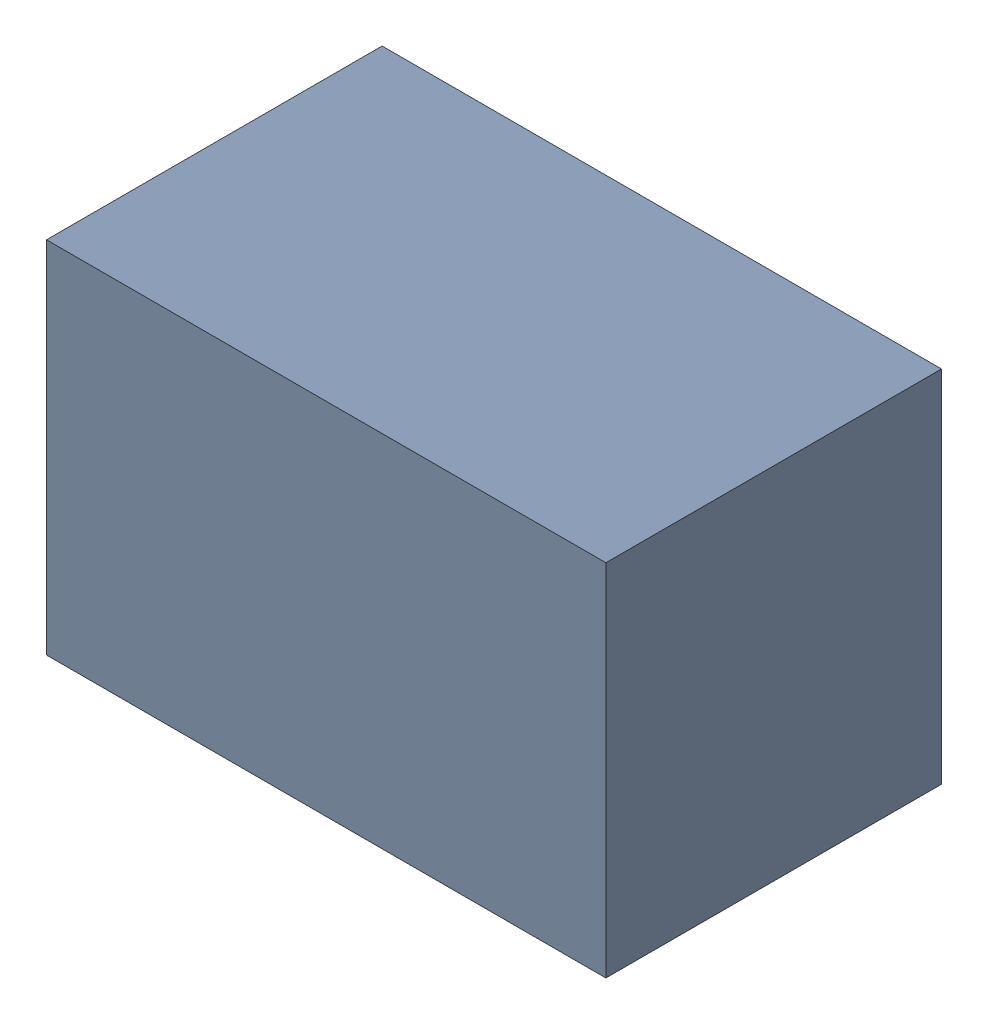
SolidWorks assembly C2_1, configuration Default. Lengths in mm.
Overall size (2.1 1.35 1.26).
2 component instances, 1 part files, 0 mates.
Components (placement in the parent):
- 407985824_1-1: 407985824_1 [Default] at (45.593 14.478 0.0127) size (2.1 1.35 1.26)
  - Extruded_7-1: Extruded_7 [Default] at origin size (2.1 1.35 1.26)
